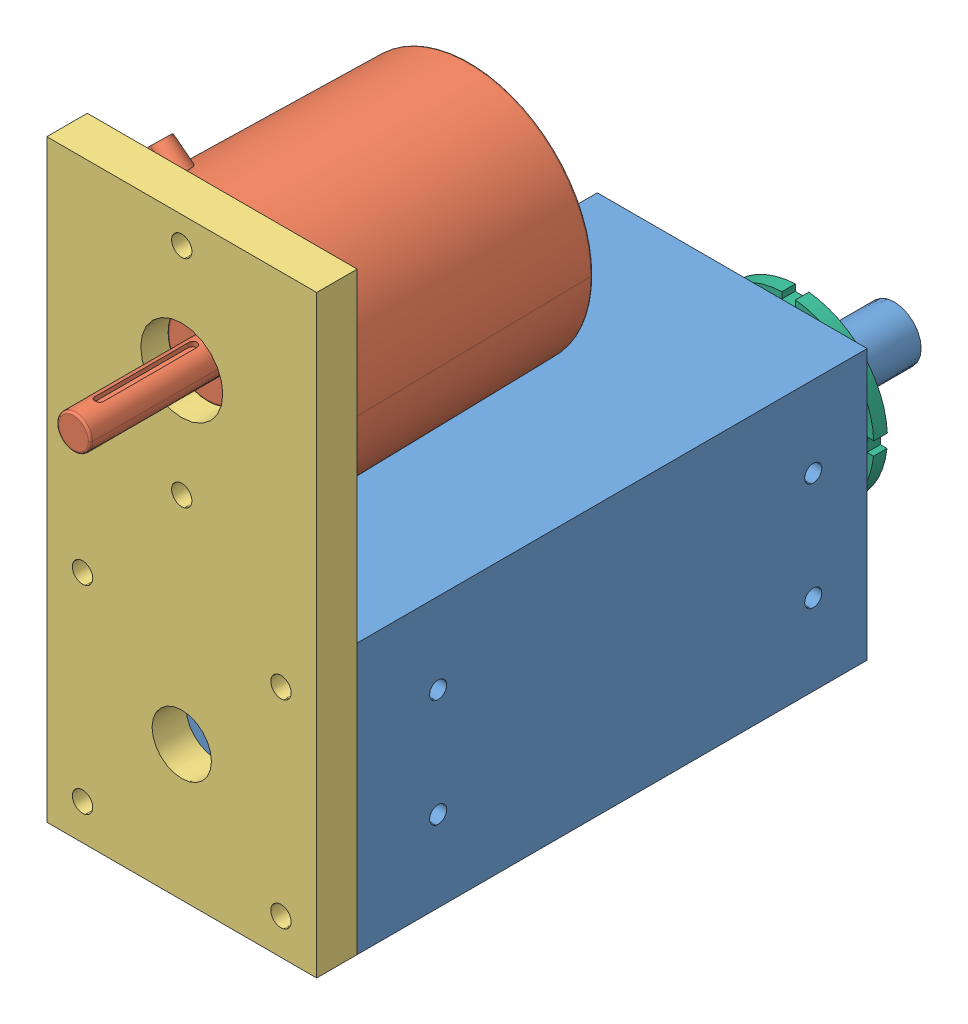
SolidWorks assembly 452-000 Climber Drive Assm, configuration Default. Lengths in mm.
Overall size (63.5 139.7 193.11).
7 component instances, 7 part files, 15 mates.
Components (placement in the parent):
- 452-001 4-Stage Banebots B220 Gearbox Model-1: 452-001 4-Stage Banebots B220 Gearbox Model [Default] at (85.4443 73.0676 113.8402) size (63.5 63.5 158.12)
- 121-002  REV Sims-1: 121-002  REV Sims [Rev 1.1] at (85.4443 149.2676 173.8477) size (61.14 61.02 93.25)
- 452-002 Rev to Gearbox Plate-1: 452-002 Rev to Gearbox Plate [Default] at (123.5443 187.3676 183.3727) x (0 -1 0) z (0 0 -1) size (139.7 63.5 9.53)
- 452-005 Adapter-1: 452-005 Adapter [Default] at (85.4443 73.0676 52.2452) x (0 0 -1) z (0.992989 -0.118208 0) size (15.88 38.1 38.1)
- 452-003 Small Sprocket-1: 452-003 Small Sprocket [Default] at (85.4443 73.0676 48.2764) x (0 0 -1) z (0.982043 0.188655 0) size (8.87 52.55 52.55)
- 452-004 Lock Ring-1: 452-004 Lock Ring [Default] at (85.4443 73.0676 37.9577) x (0 0 1) z (-0.999608 0.028015 0) size (4.1 41.15 41.15)
- 452-006 Small Sprocket Spacer-1: 452-006 Small Sprocket Spacer [Default] at (85.4443 73.0676 52.2452) x (0.746169 0.665756 0) z (0 0 1) size (19.05 19.05 1.59)
Mates (geometry in assembly coordinates):
- Coincident1: coincident: plane of 452-001 4-Stage Banebots B220 Gearbox Model-1 through (85.4443 73.0676 173.8477) normal (0 0 1); plane of 121-002  REV Sims-1 through (85.4443 149.2676 173.8477) normal (0 0 1)
- Coincident2: coincident: plane of 452-001 4-Stage Banebots B220 Gearbox Model-1 through (85.4443 73.0676 173.8477) normal (0 0 1); plane of 452-002 Rev to Gearbox Plate-1 through (123.5443 187.3676 173.8477) normal (0 0 -1)
- Concentric2: concentric: cylinder of 452-001 4-Stage Banebots B220 Gearbox Model-1 through (85.4443 73.0676 135.7477) axis (0 0 1) radius 6.35; cylinder of 452-002 Rev to Gearbox Plate-1 through (85.4443 73.0676 183.3727) axis (0 0 -1) radius 6.985
- Concentric3: concentric: cylinder of 121-002  REV Sims-1 through (85.4443 149.2676 255.1614) axis (0 0 -1) radius 4; cylinder of 452-002 Rev to Gearbox Plate-1 through (85.4443 149.2676 183.3727) axis (0 0 -1) radius 9.652
- Concentric4: concentric: cylinder of 121-002  REV Sims-1 through (85.4443 123.8676 173.8477) axis (0 0 1) radius 2.0193; cylinder of 452-002 Rev to Gearbox Plate-1 through (85.4443 123.8676 183.3727) axis (0 0 -1) radius 2.4003
- Parallel2: parallel: plane of 452-001 4-Stage Banebots B220 Gearbox Model-1 through (85.4443 73.0676 53.8327) normal (0 0 -1); plane of 452-005 Adapter-1 through (85.4443 73.0676 52.2452) normal (0 0 1)
- Concentric5: concentric: cylinder of 452-001 4-Stage Banebots B220 Gearbox Model-1 through (85.4443 73.0676 15.7327) axis (0 0 1) radius 6.35; cylinder of 452-005 Adapter-1 through (85.4443 73.0676 36.3702) axis (0 0 1) radius 6.35
- Concentric6: concentric: cylinder of 452-005 Adapter-1 through (85.4443 73.0676 49.0702) axis (0 0 1) radius 19.05; cylinder of 452-003 Small Sprocket-1 through (85.4443 73.0676 41.1327) axis (0 0 1) radius 19.05
- Coincident3: coincident: plane of 452-005 Adapter-1 through (85.4443 73.0676 49.0702) normal (0 0 -1); plane of 452-003 Small Sprocket-1 through (85.4443 73.0676 49.0702) normal (0 0 1)
- Concentric7: concentric: cylinder of 452-003 Small Sprocket-1 through (85.4443 73.0676 41.1327) axis (0 0 1) radius 19.05; cylinder of 452-004 Lock Ring-1 through (85.4443 73.0676 41.1327) axis (0 0 -1) radius 20.6375
- Coincident4: coincident: plane of 452-003 Small Sprocket-1 through (85.4443 73.0676 41.1327) normal (0 0 -1); plane of 452-004 Lock Ring-1 through (85.4443 73.0676 41.1327) normal (0 0 1)
- Coincident5: coincident: plane of 452-001 4-Stage Banebots B220 Gearbox Model-1 through (53.6943 104.8176 173.8477) normal (-1 0 0); plane of 452-002 Rev to Gearbox Plate-1 through (53.6943 41.3176 173.8477) normal (-1 0 0)
- Concentric8: concentric: cylinder of 452-001 4-Stage Banebots B220 Gearbox Model-1 through (85.4443 73.0676 15.7327) axis (0 0 1) radius 6.35; cylinder of 452-006 Small Sprocket Spacer-1 through (85.4443 73.0676 53.8327) axis (0 0 -1) radius 6.35
- Coincident7: coincident: plane of 452-001 4-Stage Banebots B220 Gearbox Model-1 through (85.4443 73.0676 53.8327) normal (0 0 -1); plane of 452-006 Small Sprocket Spacer-1 through (85.4443 73.0676 53.8327) normal (0 0 1)
- Coincident8: coincident: plane of 452-005 Adapter-1 through (85.4443 73.0676 52.2452) normal (0 0 1); plane of 452-006 Small Sprocket Spacer-1 through (85.4443 73.0676 52.2452) normal (0 0 -1)
